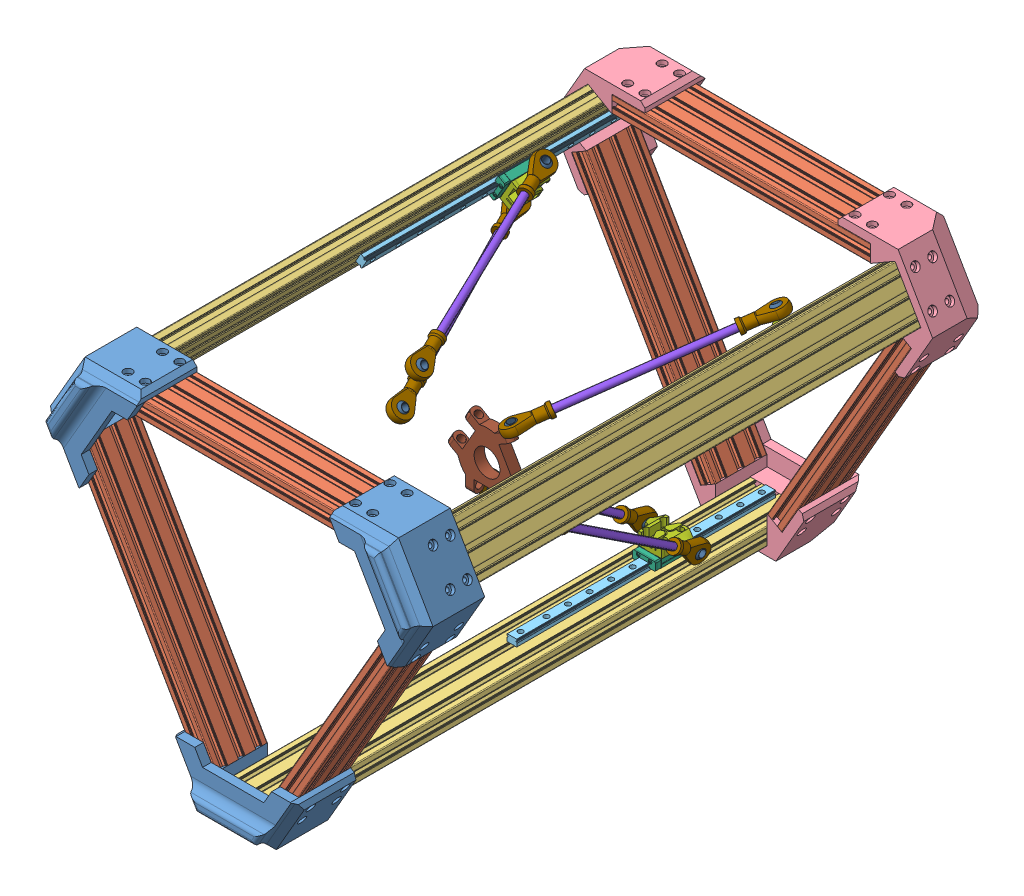
SolidWorks assembly DeltaRoboCasting, configuration Default. Lengths in mm.
Overall size (595.62 615.16 670).
78 component instances, 11 part files, 39 mates.
Components (placement in the parent):
- Bottom_Frame-1: Bottom_Frame [Default] at (236.7382 143.7809 405.9437) size (476.5 412.66 80)
  - Bottom_Corner-1: Bottom_Corner [Default] at (61.7399 88.0503 98.8697) size (145 65.62 80)
  - Connector_Perfil_VSlot_2060-1: Connector_Perfil_VSlot_2060 [默认] at (25.4632 107.1503 125.6197) x (0 0 -1) z (-0.5 0.866025 0) size (60 20 300)
  - Connector_Perfil_VSlot_2060-2: Connector_Perfil_VSlot_2060 [默认] at (102.8222 104.3758 125.6197) x (0 0 -1) z (0.5 0.866025 0) size (60 20 300)
  - Bottom_Corner-2: Bottom_Corner [Default] at (-122.9396 407.9245 98.8697) x (-0.5 -0.866025 0) z (0 0 1) size (145 65.62 80)
  - Bottom_Corner-3: Bottom_Corner [Default] at (246.4194 407.9245 98.8697) x (-0.5 0.866025 0) z (0 0 1) size (145 65.62 80)
  - Connector_Perfil_VSlot_2060-3: Connector_Perfil_VSlot_2060 [默认] at (211.7399 429.7911 132.1197) x (0 0 1) z (-1 0 0) size (60 20 300)
- Main_Perfil_VSlot_2060-1: Main_Perfil_VSlot_2060 [默认] at (483.9354 555.9073 -55.1866) x (-0.5 0.866025 0) z (0 0 1) size (60 20 600)
- Main_Perfil_VSlot_2060-2: Main_Perfil_VSlot_2060 [默认] at (117.8264 553.1328 -55.1866) x (0.5 0.866025 0) z (0 0 1) size (60 20 600)
- Main_Perfil_VSlot_2060-3: Main_Perfil_VSlot_2060 [默认] at (295.2281 234.6056 -55.1866) x (-1 0 0) z (0 0 1) size (60 20 600)
- Top_Frame-1: Top_Frame [Default] at (-6.9923 466.7993 -97.0553) x (0.5 0.866025 0) z (0 0 -1) size (476.5 412.66 70)
  - Top_Corner-1: Top_Corner [Default] at (133.9263 62.1549 -81.8687) size (145 65.62 70)
  - Connector_Perfil_VSlot_2060-4: Connector_Perfil_VSlot_2060 [默认] at (-57.1559 338.2881 -55.1187) x (0 0 -1) z (0.5 -0.866025 0) size (60 20 300)
  - Connector_Perfil_VSlot_2060-5: Connector_Perfil_VSlot_2060 [默认] at (325.0086 338.2881 -48.6187) x (0 0 1) z (-0.5 -0.866025 0) size (60 20 300)
  - Top_Corner-2: Top_Corner [Default] at (318.6058 382.0292 -81.8687) x (-0.5 0.866025 0) z (0 0 1) size (145 65.62 70)
  - Top_Corner-3: Top_Corner [Default] at (-50.7532 382.0292 -81.8687) x (-0.5 -0.866025 0) z (0 0 1) size (145 65.62 70)
  - Connector_Perfil_VSlot_2060-6: Connector_Perfil_VSlot_2060 [默认] at (-16.0737 403.8957 -55.1187) x (0 0 -1) z (1 0 0) size (60 20 300)
- MGN12H-1: MGN12H [2 X 12C] at (123.2262 537.0346 99.6767) x (-0.5 -0.866025 0) z (0 0 1) size (27 13.07 300)
  - MGN12 LINEAR GUIDE RAIL, CONFIGURABLE-1: MGN12 LINEAR GUIDE RAIL, CONFIGURABLE [200 mm] at origin size (11.97 8.07 300)
  - MGN12H, LINEAR GUIDE BLOCK-1: MGN12H, LINEAR GUIDE BLOCK [Default] at (0 0 -26.0331) size (27 10 47.52)
- Carriage-1: Carriage [Default] at (129.7214 533.2846 73.6436) x (-0.5 -0.866025 0) z (0.866025 -0.5 0) size (50.46 32.01 16.64)
- MGN12H-2: MGN12H [2 X 12C] at (468.077 546.8258 119.9996) x (-0.5 0.866025 0) z (0 0 1) size (27 13.07 300)
  - MGN12 LINEAR GUIDE RAIL, CONFIGURABLE-1: MGN12 LINEAR GUIDE RAIL, CONFIGURABLE [200 mm] at origin size (11.97 8.07 300)
  - MGN12H, LINEAR GUIDE BLOCK-1: MGN12H, LINEAR GUIDE BLOCK [Default] at (0 0 -26.0331) size (27 10 47.52)
- MGN12H-3: MGN12H [2 X 12C] at (298.8742 247.3312 101.5048) size (27 13.07 300)
  - MGN12 LINEAR GUIDE RAIL, CONFIGURABLE-1: MGN12 LINEAR GUIDE RAIL, CONFIGURABLE [200 mm] at origin size (11.97 8.07 300)
  - MGN12H, LINEAR GUIDE BLOCK-1: MGN12H, LINEAR GUIDE BLOCK [Default] at (0 0 -26.0331) size (27 10 47.52)
- Carriage-2: Carriage [Default] at (461.9282 543.2758 93.9665) x (-0.5 0.866025 0) z (-0.866025 -0.5 0) size (50.46 32.01 16.64)
- Carriage-3: Carriage [Default] at (298.8742 254.4312 75.4717) x (1 0 0) z (0 1 0) size (50.46 32.01 16.64)
- Rod-1: Rod [Default] at (419.7154 58.4885 53.4794) x (0.205368 0.784798 -0.584736) z (0.052377 0.587802 0.807308) size (24 15.04 262)
  - Rod 8mm-1: Rod 8mm [Default] at (118.3342 186.7474 140.4575) size (8 8 200)
  - ball_joint_assembly-1: ball_joint_assembly [Default] at (98.0142 147.6062 379.2591) x (1 0 0) z (0 1 0) size (24 48 15.04) (flexible)
    - pivot-1: pivot [Default] at (20.32 19.8016 39.1412) size (24 48 15)
    - ball_joint_8mm-1: ball_joint_8mm [Default] at (20.32 19.8016 39.1412) x (0.959956 0.183636 -0.211569) z (0.205368 0.052377 0.977282) size (14.76 14.76 12)
  - ball_joint_assembly-2: ball_joint_assembly [Default] at (98.0142 225.8886 101.656) x (1 0 0) z (0 -1 0) size (24 48 15.04) (flexible)
    - pivot-1: pivot [Default] at (20.32 19.8016 39.1412) size (24 48 15)
    - ball_joint_8mm-1: ball_joint_8mm [Default] at (20.32 19.8016 39.1412) x (0.959956 0.183636 -0.211569) z (0.205368 0.052377 0.977282) size (14.76 14.76 12)
- Rod-2: Rod [Default] at (481.7154 59.003 47.4145) x (0.205368 0.802107 -0.560757) z (0.052377 0.563141 0.824699) size (24 15.04 262)
  - Rod 8mm-1: Rod 8mm [Default] at (118.3342 186.7474 140.4575) size (8 8 200)
  - ball_joint_assembly-1: ball_joint_assembly [Default] at (98.0142 147.6062 379.2591) x (1 0 0) z (0 1 0) size (24 48 15.04) (flexible)
    - pivot-1: pivot [Default] at (20.32 19.8016 39.1412) size (24 48 15)
    - ball_joint_8mm-1: ball_joint_8mm [Default] at (20.32 19.8016 39.1412) x (0.959956 0.183636 -0.211569) z (0.205368 0.052377 0.977282) size (14.76 14.76 12)
  - ball_joint_assembly-2: ball_joint_assembly [Default] at (98.0142 225.8886 101.656) x (1 0 0) z (0 -1 0) size (24 48 15.04) (flexible)
    - pivot-1: pivot [Default] at (20.32 19.8016 39.1412) size (24 48 15)
    - ball_joint_8mm-1: ball_joint_8mm [Default] at (20.32 19.8016 39.1412) x (0.959956 0.183636 -0.211569) z (0.205368 0.052377 0.977282) size (14.76 14.76 12)
- Rod-3: Rod [Default] at (480.0915 414.227 -110.6443) x (0.78162 0.21413 0.585848) z (-0.499103 -0.348637 0.793315) size (24 15.04 262)
  - Rod 8mm-1: Rod 8mm [Default] at (118.3342 186.7474 140.4575) size (8 8 200)
  - ball_joint_assembly-1: ball_joint_assembly [Default] at (98.0142 147.6062 379.2591) x (1 0 0) z (0 1 0) size (24 48 15.04) (flexible)
    - pivot-1: pivot [Default] at (20.32 19.8016 39.1412) size (24 48 15)
    - ball_joint_8mm-1: ball_joint_8mm [Default] at (20.32 19.8016 39.1412) x (0.959956 0.183636 -0.211569) z (0.205368 0.052377 0.977282) size (14.76 14.76 12)
  - ball_joint_assembly-2: ball_joint_assembly [Default] at (98.0142 225.8886 101.656) x (1 0 0) z (0 -1 0) size (24 48 15.04) (flexible)
    - pivot-1: pivot [Default] at (20.32 19.8016 39.1412) size (24 48 15)
    - ball_joint_8mm-1: ball_joint_8mm [Default] at (20.32 19.8016 39.1412) x (0.959956 0.183636 -0.211569) z (0.205368 0.052377 0.977282) size (14.76 14.76 12)
- Rod-4: Rod [Default] at (508.8286 359.227 -110.0439) x (0.788313 0.217994 0.575362) z (-0.489912 -0.343331 0.801318) size (24 15.04 262)
  - Rod 8mm-1: Rod 8mm [Default] at (118.3342 186.7474 140.4575) size (8 8 200)
  - ball_joint_assembly-1: ball_joint_assembly [Default] at (98.0142 147.6062 379.2591) x (1 0 0) z (0 1 0) size (24 48 15.04) (flexible)
    - pivot-1: pivot [Default] at (20.32 19.8016 39.1412) size (24 48 15)
    - ball_joint_8mm-1: ball_joint_8mm [Default] at (20.32 19.8016 39.1412) x (0.959956 0.183636 -0.211569) z (0.205368 0.052377 0.977282) size (14.76 14.76 12)
  - ball_joint_assembly-2: ball_joint_assembly [Default] at (98.0142 225.8886 101.656) x (1 0 0) z (0 -1 0) size (24 48 15.04) (flexible)
    - pivot-1: pivot [Default] at (20.32 19.8016 39.1412) size (24 48 15)
    - ball_joint_8mm-1: ball_joint_8mm [Default] at (20.32 19.8016 39.1412) x (0.959956 0.183636 -0.211569) z (0.205368 0.052377 0.977282) size (14.76 14.76 12)
- Rod-5: Rod [Default] at (-93.296 522.5084 7.1549) x (0.672851 -0.62561 -0.394822) z (0.313974 -0.241753 0.918137) size (24 15.04 262)
  - Rod 8mm-1: Rod 8mm [Default] at (118.3342 186.7474 140.4575) size (8 8 200)
  - ball_joint_assembly-1: ball_joint_assembly [Default] at (98.0142 147.6062 379.2591) x (1 0 0) z (0 1 0) size (24 48 15.04) (flexible)
    - pivot-1: pivot [Default] at (20.32 19.8016 39.1412) size (24 48 15)
    - ball_joint_8mm-1: ball_joint_8mm [Default] at (20.32 19.8016 39.1412) x (0.959956 0.183636 -0.211569) z (0.205368 0.052377 0.977282) size (14.76 14.76 12)
  - ball_joint_assembly-2: ball_joint_assembly [Default] at (98.0142 225.8886 101.656) x (1 0 0) z (0 -1 0) size (24 48 15.04) (flexible)
    - pivot-1: pivot [Default] at (20.32 19.8016 39.1412) size (24 48 15)
    - ball_joint_8mm-1: ball_joint_8mm [Default] at (20.32 19.8016 39.1412) x (0.959956 0.183636 -0.211569) z (0.205368 0.052377 0.977282) size (14.76 14.76 12)
- Rod-6: Rod [Default] at (-125.7643 469.6625 13.0655) x (0.662053 -0.619375 -0.421972) z (0.338086 -0.255674 0.90572) size (24 15.04 262)
  - Rod 8mm-1: Rod 8mm [Default] at (118.3342 186.7474 140.4575) size (8 8 200)
  - ball_joint_assembly-1: ball_joint_assembly [Default] at (98.0142 147.6062 379.2591) x (1 0 0) z (0 1 0) size (24 48 15.04) (flexible)
    - pivot-1: pivot [Default] at (20.32 19.8016 39.1412) size (24 48 15)
    - ball_joint_8mm-1: ball_joint_8mm [Default] at (20.32 19.8016 39.1412) x (0.959956 0.183636 -0.211569) z (0.205368 0.052377 0.977282) size (14.76 14.76 12)
  - ball_joint_assembly-2: ball_joint_assembly [Default] at (98.0142 225.8886 101.656) x (1 0 0) z (0 -1 0) size (24 48 15.04) (flexible)
    - pivot-1: pivot [Default] at (20.32 19.8016 39.1412) size (24 48 15)
    - ball_joint_8mm-1: ball_joint_8mm [Default] at (20.32 19.8016 39.1412) x (0.959956 0.183636 -0.211569) z (0.205368 0.052377 0.977282) size (14.76 14.76 12)
- Mobile_Platform-1: Mobile_Platform [Default] at (301.978 442.1195 271.614) size (95.14 82.4 12)
Mates (geometry in assembly coordinates):
- Coincident1: coincident: plane of Bottom_Frame-1/Bottom_Corner-3 through (483.1576 551.7054 544.8134) normal (0 0 -1); plane of Main_Perfil_VSlot_2060-1 through (505.4499 531.0911 544.8134) normal (0 0 1)
- Coincident2: coincident: plane of Bottom_Frame-1/Bottom_Corner-3 through (476.8179 582.6862 544.8134) normal (-0.866025 -0.5 0); plane of Main_Perfil_VSlot_2060-1 through (499.9179 542.6757 544.8134) normal (0.866025 0.5 0)
- Coincident3: coincident: plane of Bottom_Frame-1/Bottom_Corner-3 through (506.8179 530.7247 544.8134) normal (-0.5 0.866025 0); plane of Main_Perfil_VSlot_2060-1 through (490.3688 521.2278 544.8134) normal (0.5 -0.866025 0)
- Coincident4: coincident: plane of Bottom_Frame-1/Bottom_Corner-2 through (113.7986 551.7054 544.8134) normal (0 0 -1); plane of Main_Perfil_VSlot_2060-2 through (107.0923 522.0926 544.8134) normal (0 0 1)
- Coincident5: coincident: plane of Bottom_Frame-1/Bottom_Corner-2 through (90.1384 530.7247 544.8134) normal (0.866025 -0.5 0); plane of Main_Perfil_VSlot_2060-2 through (103.2312 553.4022 544.8134) normal (-0.866025 0.5 0)
- Coincident6: coincident: plane of Bottom_Frame-1/Bottom_Corner-2 through (90.1384 530.7247 544.8134) normal (0.5 0.866025 0); plane of Main_Perfil_VSlot_2060-2 through (102.0942 523.8219 544.8134) normal (-0.5 -0.866025 0)
- Coincident7: coincident: plane of Bottom_Frame-1/Bottom_Corner-1 through (298.4781 231.8312 544.8134) normal (0 0 -1); plane of Main_Perfil_VSlot_2060-3 through (327.4768 240.8297 544.8134) normal (0 0 1)
- Coincident8: coincident: plane of Bottom_Frame-1/Bottom_Corner-1 through (328.4781 221.8312 544.8134) normal (0 1 0); plane of Main_Perfil_VSlot_2060-3 through (282.2826 221.8312 544.8134) normal (0 -1 0)
- Coincident9: coincident: plane of Bottom_Frame-1/Bottom_Corner-1 through (268.4781 221.8312 544.8134) normal (1 0 0); plane of Main_Perfil_VSlot_2060-3 through (268.4781 228.0257 544.8134) normal (-1 0 0)
- Coincident10: coincident: plane of Main_Perfil_VSlot_2060-1 through (505.4499 531.0911 -55.1866) normal (0 0 -1); plane of Top_Frame-1/Top_Corner-2 through (483.1576 551.7054 -55.1866) normal (0 0 1)
- Coincident11: coincident: plane of Main_Perfil_VSlot_2060-1 through (489.9107 560.0087 544.8134) normal (0.866025 0.5 0); plane of Top_Frame-1/Top_Corner-2 through (506.8179 530.7247 -55.1866) normal (-0.866025 -0.5 0)
- Coincident12: coincident: plane of Main_Perfil_VSlot_2060-1 through (490.3688 521.2278 544.8134) normal (0.5 -0.866025 0); plane of Top_Frame-1/Top_Corner-2 through (506.8179 530.7247 -55.1866) normal (-0.5 0.866025 0)
- Coincident13: coincident: plane of Main_Perfil_VSlot_2060-2 through (124.366 550.0087 544.8134) normal (0.866025 -0.5 0); plane of MGN12H-1/MGN12 LINEAR GUIDE RAIL, CONFIGURABLE-1 through (121.205 544.5337 249.6767) normal (-0.866025 0.5 0)
- Parallel1: parallel: plane of Top_Frame-1/Top_Corner-1 through (113.7986 551.7054 -75.1866) normal (0 0 1); plane of MGN12H-1/MGN12 LINEAR GUIDE RAIL, CONFIGURABLE-1 through (124.9204 542.677 -50.3233) normal (0 0 -1)
- Coincident15: coincident: plane of MGN12H-1/MGN12H, LINEAR GUIDE BLOCK-1 through (132.9214 538.8271 89.8436) normal (0.866025 -0.5 0); plane of Carriage-1 through (129.7214 533.2846 73.6436) normal (-0.866025 0.5 0)
- Concentric1: concentric: cylinder of MGN12H-1/MGN12H, LINEAR GUIDE BLOCK-1 through (124.7214 524.6243 63.6436) axis (0.866025 -0.5 0) radius 1.5; cylinder of Carriage-1 through (137.7118 517.1243 63.6436) axis (-0.866025 0.5 0) radius 1.8
- Concentric2: concentric: cylinder of MGN12H-1/MGN12H, LINEAR GUIDE BLOCK-1 through (134.7214 541.9448 63.6436) axis (0.866025 -0.5 0) radius 1.5; cylinder of Carriage-1 through (147.7118 534.4448 63.6436) axis (-0.866025 0.5 0) radius 1.8
- Coincident17: coincident: plane of Main_Perfil_VSlot_2060-1 through (476.4045 543.4022 544.8134) normal (-0.866025 -0.5 0); plane of MGN12H-2/MGN12 LINEAR GUIDE RAIL, CONFIGURABLE-1 through (475.582 544.8267 269.9996) normal (0.866025 0.5 0)
- Parallel2: parallel: plane of Top_Frame-1/Top_Corner-2 through (483.1576 551.7054 -75.1866) normal (0 0 1); plane of MGN12H-2/MGN12 LINEAR GUIDE RAIL, CONFIGURABLE-1 through (472.1165 542.5374 -30.0004) normal (0 0 -1)
- Coincident19: coincident: plane of Main_Perfil_VSlot_2060-3 through (314.6782 241.8312 544.8134) normal (0 1 0); plane of MGN12H-3/MGN12 LINEAR GUIDE RAIL, CONFIGURABLE-1 through (293.3904 241.8312 251.5048) normal (0 -1 0)
- Parallel3: parallel: plane of Top_Frame-1/Top_Corner-3 through (298.4781 231.8312 -75.1866) normal (0 0 1); plane of MGN12H-3/MGN12 LINEAR GUIDE RAIL, CONFIGURABLE-1 through (293.1406 245.9771 -48.4952) normal (0 0 -1)
- Coincident21: coincident: plane of MGN12H-2/MGN12H, LINEAR GUIDE BLOCK-1 through (458.9282 548.472 110.1665) normal (-0.866025 -0.5 0); plane of Carriage-2 through (461.9282 543.2758 93.9665) normal (0.866025 0.5 0)
- Concentric4: concentric: cylinder of MGN12H-2/MGN12H, LINEAR GUIDE BLOCK-1 through (466.5818 534.4156 83.9665) axis (-0.866025 -0.5 0) radius 1.5; cylinder of Carriage-2 through (453.9378 527.1156 83.9665) axis (0.866025 0.5 0) radius 1.8
- Concentric5: concentric: cylinder of MGN12H-2/MGN12H, LINEAR GUIDE BLOCK-1 through (456.5818 551.7361 83.9665) axis (-0.866025 -0.5 0) radius 1.5; cylinder of Carriage-2 through (443.9378 544.4361 83.9665) axis (0.866025 0.5 0) radius 1.8
- Coincident22: coincident: plane of MGN12H-3/MGN12H, LINEAR GUIDE BLOCK-1 through (304.8742 254.4312 91.6717) normal (0 1 0); plane of Carriage-3 through (298.8742 254.4312 75.4717) normal (0 -1 0)
- Concentric6: concentric: cylinder of MGN12H-3/MGN12H, LINEAR GUIDE BLOCK-1 through (308.8742 254.8312 65.4717) axis (0 1 0) radius 1.5; cylinder of Carriage-3 through (308.8742 269.4312 65.4717) axis (0 -1 0) radius 1.8
- Concentric7: concentric: cylinder of MGN12H-3/MGN12H, LINEAR GUIDE BLOCK-1 through (288.8742 254.8312 65.4717) axis (0 1 0) radius 1.5; cylinder of Carriage-3 through (288.8742 269.4312 65.4717) axis (0 -1 0) radius 1.8
- Coincident23: coincident: plane of Carriage-3 through (273.8742 259.4312 67.4717) normal (-1 0 0); plane of Rod-1/ball_joint_assembly-2/ball_joint_8mm-1 through (273.8742 263.3135 65.6231) normal (1 0 0)
- Concentric8: concentric: cylinder of Carriage-3 through (285.3742 259.4312 67.4717) axis (-1 0 0) radius 4.1; cylinder of Rod-1/ball_joint_assembly-2/ball_joint_8mm-1 through (267.8742 259.4312 67.4717) axis (-1 0 0) radius 4
- Coincident24: coincident: plane of Carriage-3 through (323.8742 259.4312 67.4717) normal (1 0 0); plane of Rod-2/ball_joint_assembly-2/ball_joint_8mm-1 through (323.8742 263.0929 65.8619) normal (-1 0 0)
- Concentric9: concentric: cylinder of Carriage-3 through (312.3742 259.4312 67.4717) axis (1 0 0) radius 4.1; cylinder of Rod-2/ball_joint_assembly-2/ball_joint_8mm-1 through (329.8742 259.4312 67.4717) axis (-1 0 0) radius 4
- Coincident25: coincident: plane of Carriage-2 through (445.0981 562.4265 85.9665) normal (-0.5 0.866025 0); plane of Rod-3/ball_joint_assembly-2/ball_joint_8mm-1 through (447.59 563.8652 89.1619) normal (0.5 -0.866025 0)
- Concentric10: concentric: cylinder of Carriage-2 through (450.8481 552.4672 85.9665) axis (-0.5 0.866025 0) radius 4.1; cylinder of Rod-3/ball_joint_assembly-2/ball_joint_8mm-1 through (442.0981 567.6226 85.9665) axis (-0.5 0.866025 0) radius 4
- Coincident26: coincident: plane of Carriage-2 through (470.0981 519.1252 85.9665) normal (0.5 -0.866025 0); plane of Rod-4/ball_joint_assembly-2/ball_joint_8mm-1 through (472.4502 520.4832 88.9031) normal (-0.5 0.866025 0)
- Concentric11: concentric: cylinder of Carriage-2 through (464.3481 529.0845 85.9665) axis (0.5 -0.866025 0) radius 4.1; cylinder of Rod-4/ball_joint_assembly-2/ball_joint_8mm-1 through (473.0981 513.929 85.9665) axis (-0.5 0.866025 0) radius 4
- Coincident27: coincident: plane of Carriage-1 through (146.5516 552.4352 65.6436) normal (0.5 0.866025 0); plane of Rod-5/ball_joint_assembly-2/ball_joint_8mm-1 through (150.1863 550.3367 64.7081) normal (-0.5 -0.866025 0)
- Concentric12: concentric: cylinder of Carriage-1 through (140.8016 542.4759 65.6436) axis (0.5 0.866025 0) radius 4.1; cylinder of Rod-5/ball_joint_assembly-2/ball_joint_8mm-1 through (149.5516 557.6314 65.6436) axis (0.5 0.866025 0) radius 4
- Coincident28: coincident: plane of Carriage-1 through (121.5516 509.1339 65.6436) normal (-0.5 -0.866025 0); plane of Rod-6/ball_joint_assembly-2/ball_joint_8mm-1 through (124.9081 507.196 64.6546) normal (0.5 0.866025 0)
- Concentric13: concentric: cylinder of Carriage-1 through (127.3016 519.0932 65.6436) axis (-0.5 -0.866025 0) radius 4.1; cylinder of Rod-6/ball_joint_assembly-2/ball_joint_8mm-1 through (118.5516 503.9378 65.6436) axis (0.5 0.866025 0) radius 4
